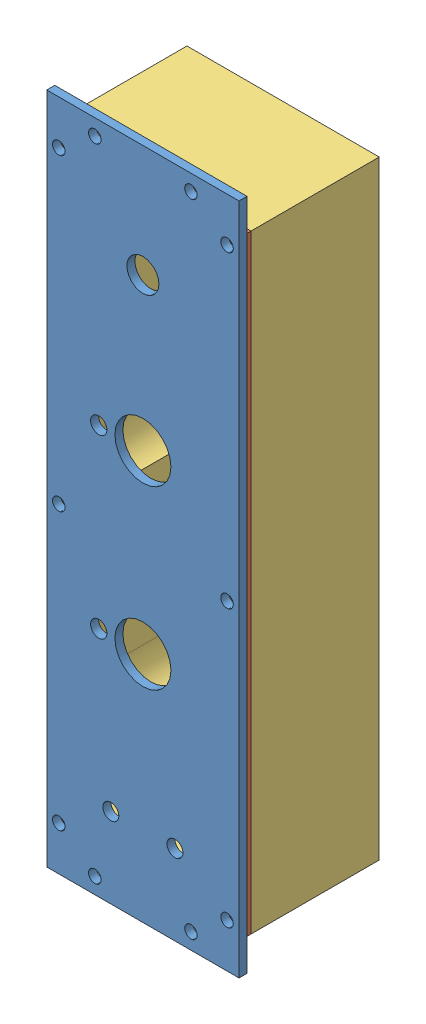
SolidWorks assembly FS2-EN-A-0001-V1, TSMP, configuration Default. Lengths in mm.
Overall size (76.2 266.7 55.56).
3 component instances, 3 part files, 4 mates.
Components (placement in the parent):
- FS2-EN-P-0001-V1, TSMP, RIGHT SIDE PANEL-1: FS2-EN-P-0001-V1, TSMP, RIGHT SIDE PANEL [Default] at (52.5062 244.5268 157.9685) size (76.2 266.7 3.17)
- FS2-EN-P-0001-V1, TSMP, GASKET-1: FS2-EN-P-0001-V1, TSMP, GASKET [Default] at (52.5062 231.8268 156.381) size (76.2 241.3 1.59)
- FS2-EN-P-0001-V1, TSMP, ENCLOSURE-1: FS2-EN-P-0001-V1, TSMP, ENCLOSURE [Default] at (52.5062 231.8268 111.931) size (76.2 241.3 50.8)
Mates (geometry in assembly coordinates):
- Concentric1: concentric: circle of FS2-EN-P-0001-V1, TSMP, GASKET-1; circle of FS2-EN-P-0001-V1, TSMP, ENCLOSURE-1
- Concentric2: concentric aligned: circle of FS2-EN-P-0001-V1, TSMP, RIGHT SIDE PANEL-1; circle of FS2-EN-P-0001-V1, TSMP, GASKET-1
- Coincident1: coincident: line of FS2-EN-P-0001-V1, TSMP, RIGHT SIDE PANEL-1 through (128.7062 -22.1732 157.9685) axis (0 1 0); point of FS2-EN-P-0001-V1, TSMP, GASKET-1
- Coincident2: coincident: line of FS2-EN-P-0001-V1, TSMP, GASKET-1 through (128.7062 -9.4732 156.381) axis (0 1 0); point of FS2-EN-P-0001-V1, TSMP, ENCLOSURE-1
